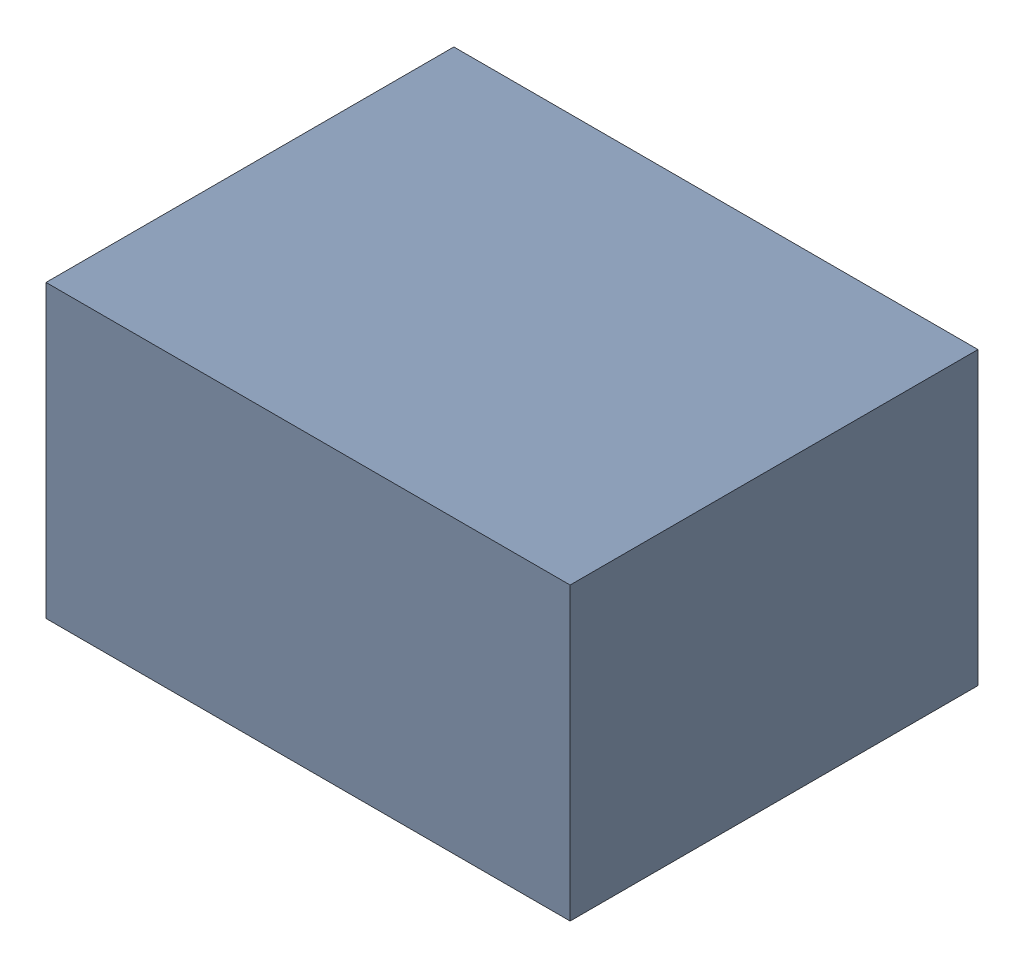
SolidWorks assembly C45, configuration Default. Lengths in mm.
Overall size (1.8 1 1.4).
3 component instances, 2 part files, 0 mates.
Components (placement in the parent):
- 1088884976-1: 1088884976 [Default] at (12.9 5.425 -3.044) size (1.8 1 1.4)
  - Extruded-47-1: Extruded-47 [Default] at origin size (1.8 1 1.4)
- C0603-1: C0603 [Default] at (12.1 5.8251 -1.644) x (1 0 0) z (0 1 0) size (1.6 0.5 0.8)
